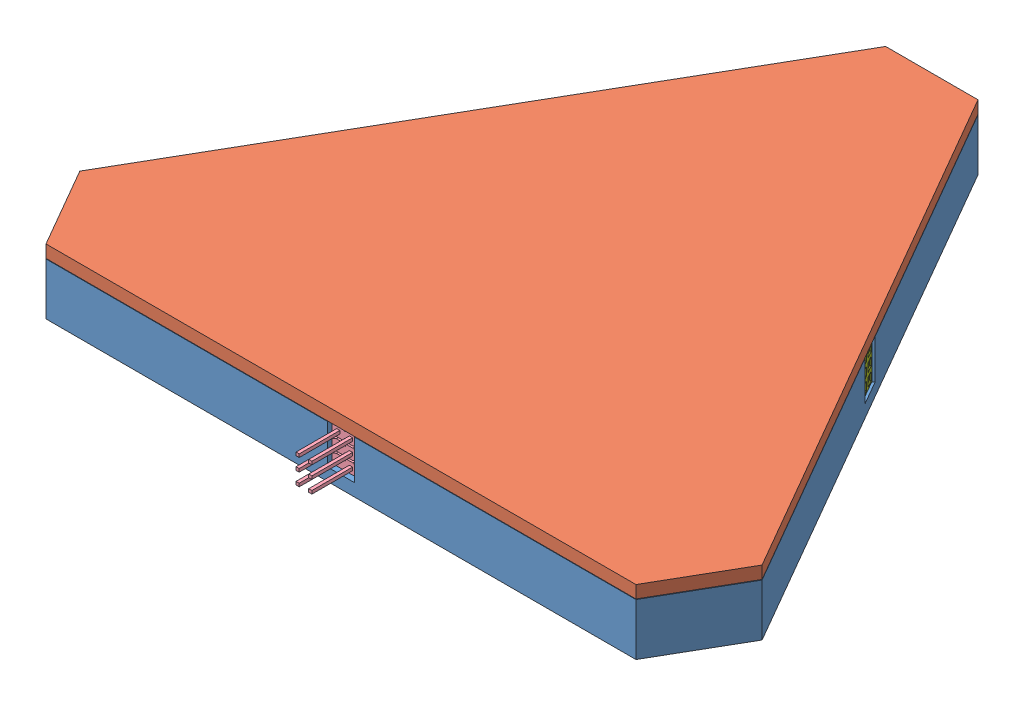
SolidWorks assembly nanoleaf_21leds, configuration Défaut. Lengths in mm.
Overall size (136.52 14.05 135.13).
16 component instances, 7 part files, 48 mates.
Components (placement in the parent):
- nanoleaf_21leds_bottom-1: nanoleaf_21leds_bottom [Défaut] at origin size (136.52 12 118.23)
- nanoleaf_21leds_top-1: nanoleaf_21leds_top [Défaut] at (0 13 0) x (1 0 0) z (0 0 -1) size (136.52 2.5 118.23)
- Strip_led_ws2812_60leds-m-1: Strip_led_ws2812_60leds-m [Défaut] at (-91.3022 6.5 75.6507) x (0.5 0 -0.866025) z (0.866025 0 0.5) size (57.63 10 59.04)
- Strip_led_ws2812_60leds-m-2: Strip_led_ws2812_60leds-m [Défaut] at (111.1665 6.5 41.2446) x (-1 0 0) z (0 0 -1) size (57.63 10 59.04)
- Strip_led_ws2812_60leds-m-3: Strip_led_ws2812_60leds-m [Défaut] at (-19.8643 6.5 -116.8953) x (0.5 0 0.866025) z (-0.866025 0 0.5) size (57.63 10 59.04)
- TSM_103_02_T_DV-1: TSM_103_02_T_DV [Défaut] at (0 6.5 42.7496) x (0 -1 0) z (-1 0 0) size (7.62 11.94 7.44)
- TS0101F020P-1: TS0101F020P [Défaut] at (29.5407 4.35 -15.3233) x (-0.5 0 -0.866025) z (0.866025 0 -0.5) size (8.31 2.7 12.18)
- TS0101F020P-5: TS0101F020P [Défaut] at (-28.0407 4.35 -17.9214) x (-0.5 0 0.866025) z (-0.866025 0 -0.5) size (8.31 2.7 12.18)
- Aimant_10x2mm-1: Aimant_10x2mm [Défaut] at (37.5 6 41.7446) x (0.78482 -0.619723 0) z (0 0 1) size (10 10 2)
- Aimant_10x2mm-2: Aimant_10x2mm [Défaut] at (-37.5 6 41.9446) x (0.873152 -0.487449 0) z (0 0 1) size (10 10 2)
- Aimant_10x2mm-4: Aimant_10x2mm [Défaut] at (-55.0751 6 11.5036) x (-0.272453 -0.838497 0.471903) z (-0.866025 0 -0.5) size (10 10 2)
- Aimant_10x2mm-6: Aimant_10x2mm [Défaut] at (-17.5751 6 -53.4483) x (-0.128011 -0.966671 0.221722) z (-0.866025 0 -0.5) size (10 10 2)
- Aimant_10x2mm-8: Aimant_10x2mm [Défaut] at (17.5751 6 -53.4483) x (-0.4998 -0.028255 -0.86568) z (0.866025 0 -0.5) size (10 10 2)
- Aimant_10x2mm-10: Aimant_10x2mm [Défaut] at (55.0751 6 11.5036) x (-0.49797 -0.09001 -0.86251) z (0.866025 0 -0.5) size (10 10 2)
- 610006243021-1: 610006243021 [Défaut] at (-36.888 6.5 -21.2973) x (0 1 0) z (-0.866025 0 -0.5) size (7.62 7.21 3.7)
- 610006243021-2: 610006243021 [Défaut] at (36.888 6.5 -21.2973) x (0 1 0) z (0.866025 0 -0.5) size (7.62 7.21 3.7)
Mates (geometry in assembly coordinates):
- Coïncidente1: coincident: plane of nanoleaf_21leds_bottom-1 through (0 0 0) normal (0 0 1); plane of assembly through (0 0 0) normal (0 0 1)
- Coïncidente2: coincident: plane of nanoleaf_21leds_bottom-1 through (0 0 0) normal (0 1 0); plane of assembly through (0 0 0) normal (0 1 0)
- Coïncidente3: coincident: plane of nanoleaf_21leds_bottom-1 through (0 0 0) normal (1 0 0); plane of assembly through (0 0 0) normal (1 0 0)
- Coïncidente5: coincident: plane of nanoleaf_21leds_top-1 through (0 13 0) normal (0 0 -1); plane of assembly through (0 0 0) normal (0 0 1)
- Coïncidente6: coincident: plane of nanoleaf_21leds_top-1 through (0 13 0) normal (1 0 0); plane of assembly through (0 0 0) normal (1 0 0)
- Coïncidente7: coincident: plane of nanoleaf_21leds_bottom-1 through (-47.1891 1 41.2446) normal (0 0 -1); plane of Strip_led_ws2812_60leds-m-1 through (-11.5665 6.5 41.2446) normal (0 0 1)
- Coïncidente8: coincident: plane of nanoleaf_21leds_bottom-1 through (-12.1244 1 -61.4893) normal (0.866025 0 0.5); plane of Strip_led_ws2812_60leds-m-1 through (-91.3022 6.5 75.6507) normal (-0.866025 0 -0.5)
- Coïncidente9: coincident: plane of nanoleaf_21leds_bottom-1 through (0 6.5 0) normal (0 1 0); plane of Strip_led_ws2812_60leds-m-1 through (-91.3022 6.5 75.6507) normal (0 1 0)
- Coïncidente10: coincident: plane of nanoleaf_21leds_bottom-1 through (0 6.5 0) normal (0 1 0); plane of Strip_led_ws2812_60leds-m-2 through (111.1665 6.5 41.2446) normal (0 1 0)
- Coïncidente11: coincident: plane of nanoleaf_21leds_bottom-1 through (59.3135 1 20.2446) normal (-0.866025 0 0.5); plane of Strip_led_ws2812_60leds-m-2 through (41.5022 6.5 -10.6054) normal (0.866025 0 -0.5)
- Coïncidente12: coincident: plane of nanoleaf_21leds_bottom-1 through (-47.1891 1 41.2446) normal (0 0 -1); plane of Strip_led_ws2812_60leds-m-2 through (111.1665 6.5 41.2446) normal (0 0 1)
- Coïncidente13: coincident: plane of nanoleaf_21leds_bottom-1 through (0 6.5 0) normal (0 1 0); plane of Strip_led_ws2812_60leds-m-3 through (-19.8643 6.5 -116.8953) normal (0 1 0)
- Coïncidente14: coincident: plane of nanoleaf_21leds_bottom-1 through (-12.1244 1 -61.4893) normal (0.866025 0 0.5); plane of Strip_led_ws2812_60leds-m-3 through (-29.9357 6.5 -30.6392) normal (-0.866025 0 -0.5)
- Coïncidente15: coincident: plane of nanoleaf_21leds_bottom-1 through (59.3135 1 20.2446) normal (-0.866025 0 0.5); plane of Strip_led_ws2812_60leds-m-3 through (-19.8643 6.5 -116.8953) normal (0.866025 0 -0.5)
- Coïncidente17: coincident: plane of TSM_103_02_T_DV-1 through (3.7211 3.6425 40.8446) normal (0 0 1); plane of Strip_led_ws2812_60leds-m-2 through (111.1665 6.5 40.8446) normal (0 0 -1)
- Coïncidente18: coincident: plane of nanoleaf_21leds_bottom-1 through (0 0 0) normal (-1 0 0); plane of TSM_103_02_T_DV-1 through (0 6.5 42.7496) normal (-1 0 0)
- Coïncidente19: coincident: plane of nanoleaf_21leds_bottom-1 through (0 6.5 0) normal (0 1 0); plane of TSM_103_02_T_DV-1 through (0 6.5 42.7496) normal (0 -1 0)
- Coïncidente28: coincident: plane of nanoleaf_21leds_bottom-1 through (0 3 0) normal (0 1 0); plane of TS0101F020P-1 through (35.1949 3 -13.38) normal (0 -1 0)
- Coaxiale3: concentric: cylinder of nanoleaf_21leds_bottom-1 through (27.4149 5.5 -16.4053) axis (0 -1 0) radius 0.7; cylinder of TS0101F020P-1 through (27.4149 2.865 -16.4053) axis (0 1 0) radius 0.8
- Coaxiale4: concentric: cylinder of nanoleaf_21leds_bottom-1 through (29.4149 5.5 -12.9412) axis (0 -1 0) radius 0.7; cylinder of TS0101F020P-1 through (29.4149 2.865 -12.9412) axis (0 1 0) radius 0.8
- Coïncidente31: coincident: plane of nanoleaf_21leds_bottom-1 through (0 12 0) normal (0 1 0); plane of nanoleaf_21leds_top-1 through (0 12 0) normal (0 -1 0)
- Distance1: distance = 0.1 mm: plane of Aimant_10x2mm-1 through (37.5 6 41.7446) normal (0 0 -1); plane of nanoleaf_21leds_bottom-1 through (32.25 -11.4539 41.8446) normal (0 0 1)
- Distance2: distance = 5.25 mm: cylinder of Aimant_10x2mm-1 through (37.5 6 43.7446) axis (0 0 -1) radius 5; plane of nanoleaf_21leds_bottom-1 through (32.25 -11.4539 41.8446) normal (1 0 0)
- Tangent1: tangent: plane of nanoleaf_21leds_bottom-1 through (0 1 -54.4893) normal (0 1 0); cylinder of Aimant_10x2mm-1 through (37.5 6 43.7446) axis (0 0 -1) radius 5
- Distance3: distance = 0.1 mm: plane of Aimant_10x2mm-2 through (-37.5 6 41.9446) normal (0 0 -1); plane of nanoleaf_21leds_bottom-1 through (-32.25 -11.4539 41.8446) normal (0 0 1)
- Distance4: distance = 5.25 mm: cylinder of Aimant_10x2mm-2 through (-37.5 6 43.9446) axis (0 0 -1) radius 5; plane of nanoleaf_21leds_bottom-1 through (-42.75 -11.4539 41.8446) normal (1 0 0)
- Tangent2: tangent: plane of nanoleaf_21leds_bottom-1 through (0 1 -54.4893) normal (0 1 0); cylinder of Aimant_10x2mm-2 through (-37.5 6 43.9446) axis (0 0 -1) radius 5
- Distance5: distance = 0.1 mm: plane of Aimant_10x2mm-4 through (-55.0751 6 11.5036) normal (0.866025 0 0.5); plane of nanoleaf_21leds_bottom-1 through (-52.3635 -11.4539 7.007) normal (-0.866025 0 -0.5)
- Distance6: distance = 5.25 mm: cylinder of Aimant_10x2mm-4 through (-56.8072 6 10.5036) axis (0.866025 0 0.5) radius 5; plane of nanoleaf_21leds_bottom-1 through (-52.3635 -11.4539 7.007) normal (-0.5 0 0.866025)
- Tangent3: tangent: plane of nanoleaf_21leds_bottom-1 through (0 1 -54.4893) normal (0 1 0); cylinder of Aimant_10x2mm-4 through (-56.8072 6 10.5036) axis (0.866025 0 0.5) radius 5
- Distance7: distance = 0.1 mm: plane of Aimant_10x2mm-6 through (-17.5751 6 -53.4483) normal (0.866025 0 0.5); plane of nanoleaf_21leds_bottom-1 through (-20.1135 -11.4539 -48.8516) normal (-0.866025 0 -0.5)
- Distance8: distance = 5.25 mm: cylinder of Aimant_10x2mm-6 through (-19.3072 6 -54.4483) axis (0.866025 0 0.5) radius 5; plane of nanoleaf_21leds_bottom-1 through (-14.8635 -11.4539 -57.9449) normal (-0.5 0 0.866025)
- Tangent4: tangent: plane of nanoleaf_21leds_bottom-1 through (0 1 -54.4893) normal (0 1 0); cylinder of Aimant_10x2mm-6 through (-19.3072 6 -54.4483) axis (0.866025 0 0.5) radius 5
- Distance9: distance = 0.1 mm: plane of Aimant_10x2mm-8 through (17.5751 6 -53.4483) normal (-0.866025 0 0.5); plane of nanoleaf_21leds_bottom-1 through (20.1135 -11.4539 -48.8516) normal (0.866025 0 -0.5)
- Distance10: distance = 5.25 mm: cylinder of Aimant_10x2mm-8 through (19.3072 6 -54.4483) axis (-0.866025 0 0.5) radius 5; plane of nanoleaf_21leds_bottom-1 through (20.1135 -11.4539 -48.8516) normal (-0.5 0 -0.866025)
- Tangent5: tangent: plane of nanoleaf_21leds_bottom-1 through (0 1 -54.4893) normal (0 1 0); cylinder of Aimant_10x2mm-8 through (19.3072 6 -54.4483) axis (-0.866025 0 0.5) radius 5
- Distance11: distance = 0.1 mm: plane of Aimant_10x2mm-10 through (55.0751 6 11.5036) normal (-0.866025 0 0.5); plane of nanoleaf_21leds_bottom-1 through (52.3635 -11.4539 7.007) normal (0.866025 0 -0.5)
- Distance12: distance = 5.25 mm: cylinder of Aimant_10x2mm-10 through (56.8072 6 10.5036) axis (-0.866025 0 0.5) radius 5; plane of nanoleaf_21leds_bottom-1 through (57.6135 -11.4539 16.1003) normal (-0.5 0 -0.866025)
- Tangent6: tangent: plane of nanoleaf_21leds_bottom-1 through (0 1 -54.4893) normal (0 1 0); cylinder of Aimant_10x2mm-10 through (56.8072 6 10.5036) axis (-0.866025 0 0.5) radius 5
- Coïncidente32: coincident: plane of nanoleaf_21leds_bottom-1 through (0 0 0) normal (-0.5 0 0.866025); plane of 610006243021-1 through (-36.888 6.5 -21.2973) normal (0.5 0 -0.866025)
- Coïncidente33: coincident: plane of nanoleaf_21leds_bottom-1 through (0 6.5 0) normal (0 1 0); plane of 610006243021-1 through (-36.888 6.5 -21.2973) normal (0 1 0)
- Coïncidente34: coincident: plane of Strip_led_ws2812_60leds-m-1 through (-90.9557 6.5 75.8507) normal (0.866025 0 0.5); plane of 610006243021-1 through (-36.3325 9.04 -18.7596) normal (-0.866025 0 -0.5)
- Coïncidente35: coincident: plane of nanoleaf_21leds_bottom-1 through (0 0 0) normal (0.5 0 0.866025); plane of 610006243021-2 through (36.888 6.5 -21.2973) normal (0.5 0 0.866025)
- Coïncidente36: coincident: plane of nanoleaf_21leds_bottom-1 through (0 6.5 0) normal (0 1 0); plane of 610006243021-2 through (36.888 6.5 -21.2973) normal (0 1 0)
- Coïncidente37: coincident: plane of Strip_led_ws2812_60leds-m-3 through (-20.2107 6.5 -116.6953) normal (-0.866025 0 0.5); plane of 610006243021-2 through (34.4125 9.04 -22.0851) normal (0.866025 0 -0.5)
- Coaxiale5: concentric: cylinder of nanoleaf_21leds_bottom-1 through (-25.9149 5.5 -19.0034) axis (0 -1 0) radius 0.7; cylinder of TS0101F020P-5 through (-25.9149 2.865 -19.0034) axis (0 1 0) radius 0.8
- Coaxiale6: concentric: circle of nanoleaf_21leds_bottom-1; cylinder of TS0101F020P-5 through (-27.9149 2.865 -15.5393) axis (0 1 0) radius 0.8
- Coïncidente38: coincident: plane of nanoleaf_21leds_bottom-1 through (0 3 0) normal (0 1 0); plane of TS0101F020P-5 through (-29.1849 3 -23.7896) normal (0 -1 0)
